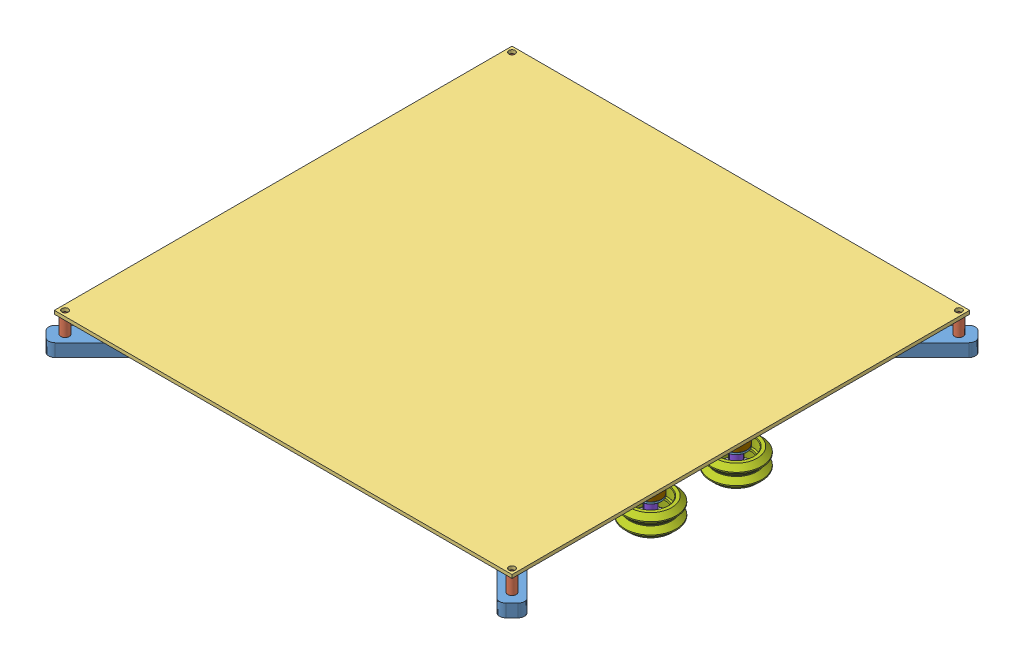
SolidWorks assembly y-bed, configuration Default. Lengths in mm.
Overall size (222.5 34.74 222.5).
48 component instances, 9 part files, 37 mates.
Components (placement in the parent):
- y-carriage-1: y-carriage [Default] at (98.8556 128.0325 168.4212) size (222.5 6 222.5)
- M3 Spacer-1: M3 Spacer [Default] at (-5.6444 134.0325 272.9212) size (4 8 4)
- M3 Spacer-2: M3 Spacer [Default] at (203.3556 134.0325 63.9212) size (4 8 4)
- M3 Spacer-3: M3 Spacer [Default] at (203.3556 134.0325 272.9212) size (4 8 4)
- M3 Spacer-4: M3 Spacer [Default] at (-5.6444 134.0325 63.9212) size (4 8 4)
- heated-bed-1: heated-bed [Default] at (98.8556 142.0325 168.4212) size (214 1.6 214)
- Eccentric Delrin Assembly-1: Eccentric Delrin Assembly [Default] at (53.5325 127.0325 167.6503) x (0 -1 0) z (0.219078 0 0.975707) size (31.75 27.59 27.59)
  - Steel Eccentric Spacer-1: Steel Eccentric Spacer [6mm - Mini] at origin size (8.5 9.09 8.71)
  - Precision Shim 10x5x1mm-1: Precision Shim 10x5x1mm [Default] at (6 0 0.79) x (-1 0 0) z (0 0.812589 -0.582837) size (1 10 10)
  - Nylon Insert Hex Locknut M5-1: Nylon Insert Hex Locknut M5 [Default] at (-7 0 0.79) x (0 -0.700969 -0.713192) z (-1 0 0) size (7.68 8.82 4.5)
  - Dual V-Wheel Delrin-1: Dual V-Wheel Delrin [Default] at (11.115 0 0.79) x (0 0.169483 -0.985533) z (1 0 0) size (23.89 23.89 10.23)
  - 5mm Low Profile Socket Head Screw-1: 5mm Low Profile Socket Head Screw [5mm x 30mm Low Profile Screw] at (17.98 0 0.79) x (-1 0 0) z (0 -0.935654 -0.352919) size (31.75 9.5 9.5)
- Delrin Assembly-1: Delrin Assembly [Default] at (14.0056 122.0325 188.4212) x (0 1 0) z (0.597414 0 0.801933) size (31.75 33.75 33.75)
  - Aluminum Spacer-1: Aluminum Spacer [6mm] at origin size (6 10 10)
  - Precision Shim 10x5x1mm-1: Precision Shim 10x5x1mm [Default] at (-1 0 0) x (1 0 0) z (0 0.993706 0.112022) size (1 10 10)
  - Dual V-Wheel Delrin-1: Dual V-Wheel Delrin [Default] at (-6.115 0 0) x (0 -0.740375 0.672194) z (-1 0 0) size (23.89 23.89 10.23)
  - Nylon Insert Hex Locknut M5-1: Nylon Insert Hex Locknut M5 [Default] at (12 0 0) x (0 -0.231787 0.972767) z (1 0 0) size (7.68 8.82 4.5)
  - 5mm Low Profile Socket Head Screw-1: 5mm Low Profile Socket Head Screw [5mm x 30mm Low Profile Screw] at (-12.98 0 0) x (1 0 0) z (0 0.597414 0.801933) size (31.75 9.5 9.5)
- Delrin Assembly-2: Delrin Assembly [Default] at (14.0056 122.0325 148.4212) x (0 1 0) z (0.597414 0 0.801933) size (31.75 33.75 33.75)
  - Aluminum Spacer-1: Aluminum Spacer [6mm] at origin size (6 10 10)
  - Precision Shim 10x5x1mm-1: Precision Shim 10x5x1mm [Default] at (-1 0 0) x (1 0 0) z (0 0.993706 0.112022) size (1 10 10)
  - Dual V-Wheel Delrin-1: Dual V-Wheel Delrin [Default] at (-6.115 0 0) x (0 -0.740375 0.672194) z (-1 0 0) size (23.89 23.89 10.23)
  - Nylon Insert Hex Locknut M5-1: Nylon Insert Hex Locknut M5 [Default] at (12 0 0) x (0 -0.231787 0.972767) z (1 0 0) size (7.68 8.82 4.5)
  - 5mm Low Profile Socket Head Screw-1: 5mm Low Profile Socket Head Screw [5mm x 30mm Low Profile Screw] at (-12.98 0 0) x (1 0 0) z (0 0.597414 0.801933) size (31.75 9.5 9.5)
- Eccentric Delrin Assembly-2: Eccentric Delrin Assembly [Default] at (143.8325 127.0325 167.6503) x (0 -1 0) z (0.219078 0 0.975707) size (31.75 27.59 27.59)
  - Steel Eccentric Spacer-1: Steel Eccentric Spacer [6mm - Mini] at origin size (8.5 9.09 8.71)
  - Precision Shim 10x5x1mm-1: Precision Shim 10x5x1mm [Default] at (6 0 0.79) x (-1 0 0) z (0 0.812589 -0.582837) size (1 10 10)
  - Nylon Insert Hex Locknut M5-1: Nylon Insert Hex Locknut M5 [Default] at (-7 0 0.79) x (0 -0.700969 -0.713192) z (-1 0 0) size (7.68 8.82 4.5)
  - Dual V-Wheel Delrin-1: Dual V-Wheel Delrin [Default] at (11.115 0 0.79) x (0 0.169483 -0.985533) z (1 0 0) size (23.89 23.89 10.23)
  - 5mm Low Profile Socket Head Screw-1: 5mm Low Profile Socket Head Screw [5mm x 30mm Low Profile Screw] at (17.98 0 0.79) x (-1 0 0) z (0 -0.935654 -0.352919) size (31.75 9.5 9.5)
- Copy of Assem1^y-bed-1: Copy of Assem1^y-bed [Default] at (183.7056 122.0325 148.4212) x (0 1 0) z (0.597414 0 0.801933) size (31.75 33.75 33.75) (virtual)
  - Aluminum Spacer-1: Aluminum Spacer [6mm] at origin size (6 10 10)
  - Precision Shim 10x5x1mm-1: Precision Shim 10x5x1mm [Default] at (-1 0 0) x (1 0 0) z (0 0.993706 0.112022) size (1 10 10)
  - Dual V-Wheel Delrin-1: Dual V-Wheel Delrin [Default] at (-6.115 0 0) x (0 -0.740375 0.672194) z (-1 0 0) size (23.89 23.89 10.23)
  - Nylon Insert Hex Locknut M5-1: Nylon Insert Hex Locknut M5 [Default] at (12 0 0) x (0 -0.231787 0.972767) z (1 0 0) size (7.68 8.82 4.5)
  - 5mm Low Profile Socket Head Screw-1: 5mm Low Profile Socket Head Screw [5mm x 30mm Low Profile Screw] at (-12.98 0 0) x (1 0 0) z (0 0.597414 0.801933) size (31.75 9.5 9.5)
- Delrin Assembly-4: Delrin Assembly [Default] at (183.7056 122.0325 188.4212) x (0 1 0) z (0.597414 0 0.801933) size (31.75 33.75 33.75)
  - Aluminum Spacer-1: Aluminum Spacer [6mm] at origin size (6 10 10)
  - Precision Shim 10x5x1mm-1: Precision Shim 10x5x1mm [Default] at (-1 0 0) x (1 0 0) z (0 0.993706 0.112022) size (1 10 10)
  - Dual V-Wheel Delrin-1: Dual V-Wheel Delrin [Default] at (-6.115 0 0) x (0 -0.740375 0.672194) z (-1 0 0) size (23.89 23.89 10.23)
  - Nylon Insert Hex Locknut M5-1: Nylon Insert Hex Locknut M5 [Default] at (12 0 0) x (0 -0.231787 0.972767) z (1 0 0) size (7.68 8.82 4.5)
  - 5mm Low Profile Socket Head Screw-1: 5mm Low Profile Socket Head Screw [5mm x 30mm Low Profile Screw] at (-12.98 0 0) x (1 0 0) z (0 0.597414 0.801933) size (31.75 9.5 9.5)
- 5mm Low Profile Socket Head Screw-1: 5mm Low Profile Socket Head Screw [5mm x 25mm Low Profile Screw] at (98.8556 135.7825 158.4212) x (0 -1 0) z (0.546944 0 -0.837169) size (26.75 9.5 9.5)
- 5mm Low Profile Socket Head Screw-2: 5mm Low Profile Socket Head Screw [5mm x 25mm Low Profile Screw] at (98.8556 135.7825 178.4212) x (0 -1 0) z (0.546944 0 -0.837169) size (26.75 9.5 9.5)
- Nylon Insert Hex Locknut M5-1: Nylon Insert Hex Locknut M5 [Default] at (98.8556 128.0325 178.4212) x (1 0 0) z (0 -1 0) size (7.68 8.82 4.5)
- Nylon Insert Hex Locknut M5-2: Nylon Insert Hex Locknut M5 [Default] at (98.8556 113.3925 178.4212) x (1 0 0) z (0 -1 0) size (7.68 8.82 4.5)
- Nylon Insert Hex Locknut M5-3: Nylon Insert Hex Locknut M5 [Default] at (98.8556 113.3925 158.4212) x (1 0 0) z (0 -1 0) size (7.68 8.82 4.5)
- Nylon Insert Hex Locknut M5-4: Nylon Insert Hex Locknut M5 [Default] at (98.8556 128.0325 158.4212) x (1 0 0) z (0 -1 0) size (7.68 8.82 4.5)
Mates (geometry in assembly coordinates):
- Coincident1: coincident aligned: plane of y-carriage-1 through (204.2759 134.0325 60.1724) normal (0 1 0); circle of M3 Spacer-1
- Concentric1: concentric aligned: cylinder of y-carriage-1 through (-5.6444 134.0325 272.9212) axis (0 -1 0) radius 1.55; cylinder of M3 Spacer-1 through (-5.6444 142.0325 272.9212) axis (0 -1 0) radius 1.5
- Concentric2: concentric aligned: cylinder of y-carriage-1 through (-5.6444 134.0325 63.9212) axis (0 -1 0) radius 1.55; cylinder of M3 Spacer-4 through (-5.6444 142.0325 63.9212) axis (0 -1 0) radius 1.5
- Coincident4: coincident anti-aligned: plane of y-carriage-1 through (204.2759 134.0325 60.1724) normal (0 1 0); plane of M3 Spacer-4 through (-5.6444 134.0325 63.9212) normal (0 -1 0)
- Concentric3: concentric aligned: cylinder of y-carriage-1 through (203.3556 134.0325 272.9212) axis (0 -1 0) radius 1.55; cylinder of M3 Spacer-3 through (203.3556 142.0325 272.9212) axis (0 -1 0) radius 1.5
- Coincident5: coincident anti-aligned: plane of y-carriage-1 through (204.2759 134.0325 60.1724) normal (0 1 0); plane of M3 Spacer-3 through (203.3556 134.0325 272.9212) normal (0 -1 0)
- Concentric4: concentric aligned: cylinder of y-carriage-1 through (203.3556 134.0325 63.9212) axis (0 -1 0) radius 1.55; cylinder of M3 Spacer-2 through (203.3556 142.0325 63.9212) axis (0 -1 0) radius 1.5
- Coincident6: coincident anti-aligned: plane of y-carriage-1 through (204.2759 134.0325 60.1724) normal (0 1 0); plane of M3 Spacer-2 through (203.3556 134.0325 63.9212) normal (0 -1 0)
- Coincident7: coincident anti-aligned: circle of M3 Spacer-1; plane of heated-bed-1 through (98.8556 142.0325 168.4212) normal (0 -1 0)
- Concentric5: concentric aligned: cylinder of M3 Spacer-1 through (-5.6444 142.0325 272.9212) axis (0 -1 0) radius 1.5; cylinder of heated-bed-1 through (-5.6444 143.6325 272.9212) axis (0 -1 0) radius 1.5
- Concentric6: concentric aligned: cylinder of y-carriage-1 through (203.3556 134.0325 63.9212) axis (0 -1 0) radius 1.55; cylinder of heated-bed-1 through (203.3556 143.6325 63.9212) axis (0 -1 0) radius 1.5
- Coincident72: coincident anti-aligned: plane of y-carriage-1 through (204.2759 128.0325 60.1724) normal (0 -1 0); plane of Delrin Assembly-1/Aluminum Spacer-1 through (14.0056 128.0325 188.4212) normal (0 1 0)
- Coincident73: coincident anti-aligned: plane of y-carriage-1 through (204.2759 134.0325 60.1724) normal (0 1 0); plane of Delrin Assembly-1/Nylon Insert Hex Locknut M5-1 through (14.0056 134.0325 188.4212) normal (0 -1 0)
- Concentric73: concentric anti-aligned: cylinder of y-carriage-1 through (14.0056 128.0325 188.4212) axis (0 1 0) radius 2.5; cylinder of Delrin Assembly-1/5mm Low Profile Socket Head Screw-1 through (14.0056 109.0525 188.4212) axis (0 -1 0) radius 2.5
- Concentric74: concentric anti-aligned: cylinder of y-carriage-1 through (14.0056 128.0325 148.4212) axis (0 1 0) radius 2.5; cylinder of Delrin Assembly-2/5mm Low Profile Socket Head Screw-1 through (14.0056 109.0525 148.4212) axis (0 -1 0) radius 2.5
- Coincident74: coincident anti-aligned: plane of y-carriage-1 through (204.2759 134.0325 60.1724) normal (0 1 0); plane of Delrin Assembly-2/Nylon Insert Hex Locknut M5-1 through (14.0056 134.0325 148.4212) normal (0 -1 0)
- Coincident75: coincident anti-aligned: plane of y-carriage-1 through (204.2759 128.0325 60.1724) normal (0 -1 0); plane of Eccentric Delrin Assembly-1/Steel Eccentric Spacer-1 through (53.5325 128.0325 167.6503) normal (0 1 0)
- Coincident76: coincident anti-aligned: plane of y-carriage-1 through (204.2759 134.0325 60.1724) normal (0 1 0); plane of Eccentric Delrin Assembly-1/Nylon Insert Hex Locknut M5-1 through (53.7056 134.0325 168.4212) normal (0 -1 0)
- Concentric75: concentric anti-aligned: cylinder of y-carriage-1 through (53.7056 128.0325 168.4212) axis (0 1 0) radius 3.6; cylinder of Eccentric Delrin Assembly-1/5mm Low Profile Socket Head Screw-1 through (53.7056 109.0525 168.4212) axis (0 -1 0) radius 2.5
- Coincident77: coincident anti-aligned: plane of y-carriage-1 through (204.2759 134.0325 60.1724) normal (0 1 0); plane of Eccentric Delrin Assembly-2/Nylon Insert Hex Locknut M5-1 through (144.0056 134.0325 168.4212) normal (0 -1 0)
- Coincident78: coincident anti-aligned: plane of y-carriage-1 through (204.2759 134.0325 60.1724) normal (0 1 0); plane of Copy of Assem1^y-bed-1/Nylon Insert Hex Locknut M5-1 through (183.7056 134.0325 148.4212) normal (0 -1 0)
- Coincident79: coincident anti-aligned: plane of y-carriage-1 through (204.2759 134.0325 60.1724) normal (0 1 0); plane of Delrin Assembly-4/Nylon Insert Hex Locknut M5-1 through (183.7056 134.0325 188.4212) normal (0 -1 0)
- Concentric80: concentric aligned: cylinder of y-carriage-1 through (98.8556 128.0325 158.4212) axis (0 1 0) radius 2.5; cylinder of 5mm Low Profile Socket Head Screw-1 through (98.8556 135.7825 158.4212) axis (0 1 0) radius 2.5
- Coincident82: coincident anti-aligned: plane of y-carriage-1 through (204.2759 134.0325 60.1724) normal (0 1 0); plane of 5mm Low Profile Socket Head Screw-1 through (96.7626 134.0325 157.0538) normal (0 -1 0)
- Concentric81: concentric aligned: cylinder of y-carriage-1 through (98.8556 128.0325 178.4212) axis (0 1 0) radius 2.5; cylinder of 5mm Low Profile Socket Head Screw-2 through (98.8556 135.7825 178.4212) axis (0 1 0) radius 2.5
- Coincident83: coincident anti-aligned: plane of y-carriage-1 through (204.2759 134.0325 60.1724) normal (0 1 0); plane of 5mm Low Profile Socket Head Screw-2 through (96.7626 134.0325 177.0538) normal (0 -1 0)
- Concentric82: concentric anti-aligned: cylinder of 5mm Low Profile Socket Head Screw-2 through (98.8556 135.7825 178.4212) axis (0 1 0) radius 2.5; cylinder of Nylon Insert Hex Locknut M5-1 through (98.8556 128.0325 178.4212) axis (0 -1 0) radius 2.5
- Coincident84: coincident anti-aligned: plane of y-carriage-1 through (204.2759 128.0325 60.1724) normal (0 -1 0); plane of Nylon Insert Hex Locknut M5-1 through (98.8556 128.0325 178.4212) normal (0 1 0)
- Concentric83: concentric anti-aligned: cylinder of 5mm Low Profile Socket Head Screw-1 through (98.8556 135.7825 158.4212) axis (0 1 0) radius 2.5; cylinder of Nylon Insert Hex Locknut M5-4 through (98.8556 128.0325 158.4212) axis (0 -1 0) radius 2.5
- Coincident85: coincident anti-aligned: plane of y-carriage-1 through (204.2759 128.0325 60.1724) normal (0 -1 0); plane of Nylon Insert Hex Locknut M5-4 through (98.8556 128.0325 158.4212) normal (0 1 0)
- Concentric84: concentric anti-aligned: cylinder of 5mm Low Profile Socket Head Screw-2 through (98.8556 135.7825 178.4212) axis (0 1 0) radius 2.5; cylinder of Nylon Insert Hex Locknut M5-2 through (98.8556 113.3925 178.4212) axis (0 -1 0) radius 2.5
- Coincident86: coincident aligned: plane of 5mm Low Profile Socket Head Screw-2 through (98.8556 109.0325 178.4212) normal (0 -1 0); plane of Nylon Insert Hex Locknut M5-2 through (98.8556 109.0325 178.4212) normal (0 -1 0)
- Concentric85: concentric anti-aligned: cylinder of 5mm Low Profile Socket Head Screw-1 through (98.8556 135.7825 158.4212) axis (0 1 0) radius 2.5; cylinder of Nylon Insert Hex Locknut M5-3 through (98.8556 113.3925 158.4212) axis (0 -1 0) radius 2.5
- Coincident87: coincident aligned: plane of 5mm Low Profile Socket Head Screw-1 through (98.8556 109.0325 158.4212) normal (0 -1 0); plane of Nylon Insert Hex Locknut M5-3 through (98.8556 109.0325 158.4212) normal (0 -1 0)
- Concentric86: concentric anti-aligned: cylinder of y-carriage-1 through (183.7056 128.0325 148.4212) axis (0 1 0) radius 2.5; cylinder of Copy of Assem1^y-bed-1/5mm Low Profile Socket Head Screw-1 through (183.7056 109.0525 148.4212) axis (0 -1 0) radius 2.5
- Concentric87: concentric anti-aligned: cylinder of y-carriage-1 through (144.0056 128.0325 168.4212) axis (0 1 0) radius 3.6; cylinder of Eccentric Delrin Assembly-2/5mm Low Profile Socket Head Screw-1 through (144.0056 109.0525 168.4212) axis (0 -1 0) radius 2.5
- Concentric88: concentric anti-aligned: cylinder of y-carriage-1 through (183.7056 128.0325 188.4212) axis (0 1 0) radius 2.5; cylinder of Delrin Assembly-4/5mm Low Profile Socket Head Screw-1 through (183.7056 109.0525 188.4212) axis (0 -1 0) radius 2.5
